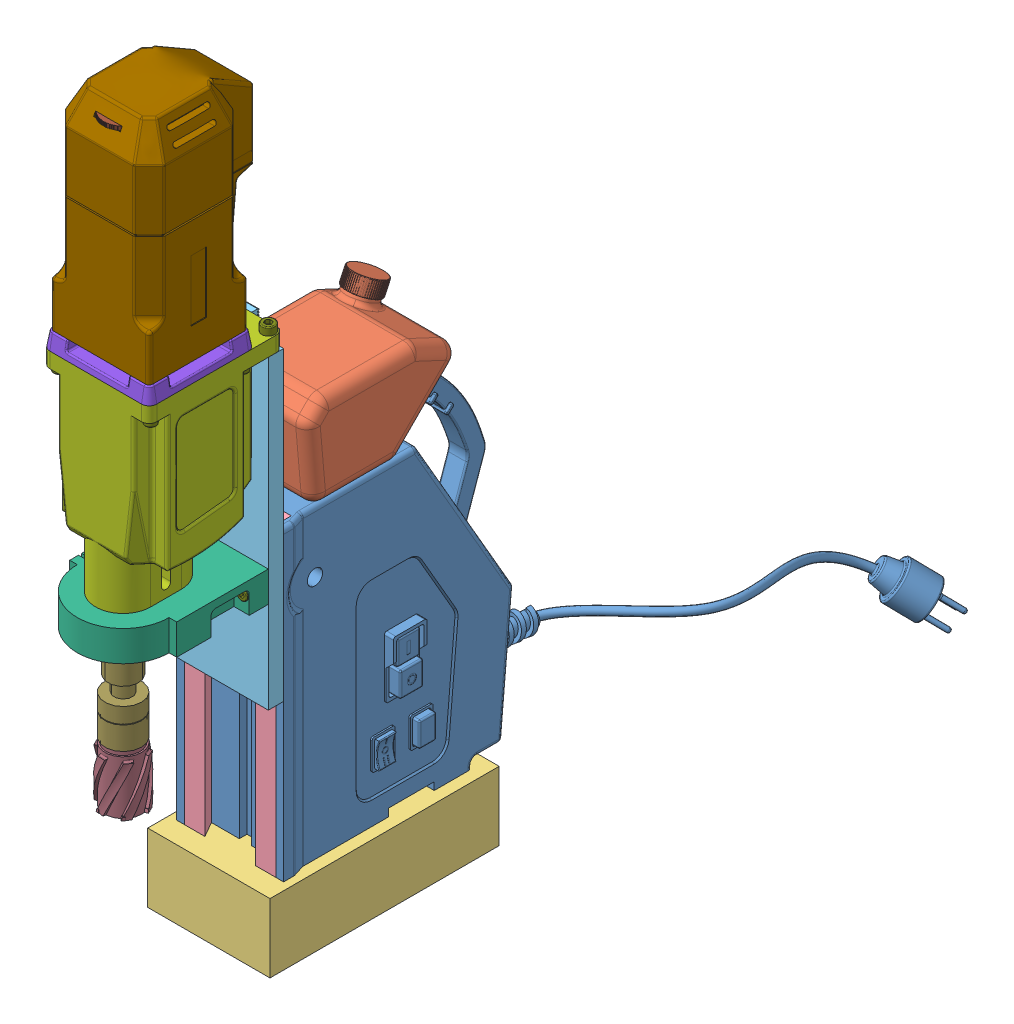
SolidWorks assembly Mag Drill, configuration Default. Lengths in mm.
Overall size (118.4 508.31 511.36).
24 component instances, 17 part files, 55 mates.
Components (placement in the parent):
- base-1: base [Default] at (-29.8336 -124.779 100.0225) size (112.65 272.37 411.36)
- water tank-1: water tank [Default] at (-29.8336 75.221 80.0225) size (75 87.59 99.86)
- Bottom electomagnit-1: Bottom electomagnit [Default] at (-29.8336 -169.779 38.9505) x (0 0 1) z (-1 0 0) size (150 45 80)
- fixed plate-1: fixed plate [Default] at (-29.8336 -124.779 95.0225) x (-1 0 0) z (0 0 -1) size (60 200 10)
- sliding plate-1: sliding plate [Default] at (-29.8336 177.5573 90.0225) x (1 0 0) z (0 0 -1) size (70 200 25)
- drill fixed plate-1: drill fixed plate [Default] at (-29.8336 37.5573 140.0225) x (-1 0 0) z (0 0 -1) size (70 20 90)
- drill floor fixed platform-1: drill floor fixed platform [Default] at (-29.8336 57.5573 160.0225) size (70.5 130 88)
- motor fixing plate-1: motor fixing plate [Default] at (-29.8336 187.5573 153.0225) size (70 10 70)
- motor-1: motor [默认] at (-29.8336 227.5573 153.0225) x (0 0 -1) z (0 -1 0) size (81.35 64.8 162.97)
- knob-1: knob [Default] at (-60.8336 142.5573 150.0225) x (-1 0 0) z (0 -0.897784 -0.440436) size (10 29 29)
- knob2-2: knob2 [Default] at (-29.8336 327.5573 170.4201) x (0.971097 0 0.238684) z (-0.238684 0 0.971097) size (24.99 2.5 24.99)
- drill fixture-1: drill fixture [Default] at (-29.8336 35.5573 170.0225) x (-0.675418 0 -0.737435) z (-0.737435 0 0.675418) size (24 110.5 24)
- drill-1: drill [Default] at (-29.8336 -62.9427 170.0225) x (0.989156 0 0.146869) z (-0.146869 0 0.989156) size (27.89 50.01 31.09)
- angular contact ball bearings gb-1: angular contact ball bearings gb [Rolling bearings S7200 GB 292-94] at (-29.8336 42.0573 170.0225) x (0 -1 0) z (0 0 1) size (9 30 30)
- cross recessed pan head screws gb-1: cross recessed pan head screws gb [GB_CROSS_SCREWS_TYPE1 M6X14-14  H type-S] at (-66.9336 35.221 77.0225) x (1 0 0) z (0 0.76934 0.638839) size (18.56 12 12)
- hexagon socket head cap screws gb-1: hexagon socket head cap screws gb [GB_FASTENER_SCREWS_HSHCS M4X10-S] at (0.1664 173.5573 182.0225) x (0 1 0) z (0 0 1) size (14 7 7)
- hexagon socket head cap screws gb-2: hexagon socket head cap screws gb [GB_FASTENER_SCREWS_HSHCS M4X10-S] at (-59.8336 173.5573 182.0225) x (0 1 0) z (0 0 1) size (14 7 7)
- hexagon socket head cap screws gb-3: hexagon socket head cap screws gb [GB_FASTENER_SCREWS_HSHCS M4X10-S] at (0.1664 173.5573 122.0225) x (0 1 0) z (0 0 1) size (14 7 7)
- hexagon socket head cap screws gb-4: hexagon socket head cap screws gb [GB_FASTENER_SCREWS_HSHCS M4X10-S] at (-59.8336 173.5573 122.0225) x (0 1 0) z (0 0 1) size (14 7 7)
- hexagon socket head cap screws gb-6: hexagon socket head cap screws gb [GB_FASTENER_SCREWS_HSHCS M5X12-S] at (0.1664 192.5573 105.0225) x (0 -1 0) z (-0.996731 0 -0.080796) size (17 8.5 8.5)
- hexagon socket head cap screws gb-7: hexagon socket head cap screws gb [GB_FASTENER_SCREWS_HSHCS M5X12-S] at (-59.8336 192.5573 105.0225) x (0 -1 0) z (-0.996731 0 -0.080796) size (17 8.5 8.5)
- hexagon socket head cap screws gb-8: hexagon socket head cap screws gb [GB_FASTENER_SCREWS_HSHCS M4X6-S] at (-60.8336 47.5573 123.5225) x (0 0 -1) z (1 0 0) size (10 7 7)
- hexagon socket head cap screws gb-11: hexagon socket head cap screws gb [GB_FASTENER_SCREWS_HSHCS M4X6-S] at (1.1664 47.5573 123.5225) x (0 0 -1) z (1 0 0) size (10 7 7)
- hexagon socket button head screws gb-1: hexagon socket button head screws gb [GB_SOCKET_TYPE7 M3X12-S] at (-60.8336 47.5573 166.6725) x (0 0 -1) z (0.073283 0.997311 0) size (13.65 5.7 5.7)
Mates (geometry in assembly coordinates):
- 重合1: coincident aligned: plane of base-1 through (-29.8336 -124.779 100.0225) normal (1 0 0); plane of water tank-1 through (-29.8336 75.221 80.0225) normal (1 0 0)
- 重合2: coincident aligned: plane of base-1 through (2.6664 75.221 100.0225) normal (0 1 0); plane of water tank-1 through (-29.8336 75.221 80.0225) normal (0 1 0)
- 距离1: distance = 10 mm: plane of assembly; plane of base-1 through (0.1664 -124.78 90.0225) normal (0 0 1); plane of water tank-1 through (-29.8336 75.221 80.0225) normal (0 0 1)
- 重合3: coincident anti-aligned: plane of base-1 through (2.6664 -124.779 -26.0495) normal (0 -1 0); plane of Bottom electomagnit-1 through (-29.8336 -124.779 38.9505) normal (0 1 0)
- 重合6: coincident anti-aligned: plane of base-1 through (-29.8336 -124.779 100.0225) normal (1 0 0); plane of Bottom electomagnit-1 through (-29.8336 -169.779 38.9505) normal (-1 0 0)
- 距离4: distance = 10 mm aligned: plane of base-1 through (2.6664 -119.779 -26.0495) normal (0 0 -1); plane of Bottom electomagnit-1 through (10.1664 -124.779 -36.0495) normal (0 0 -1)
- 重合10: coincident: plane of assembly; plane of base-1 through (0.1664 -124.78 90.0225) normal (0 0 1); plane of fixed plate-1 through (0.1664 75.221 90.0225) normal (0 0 -1)
- 重合11: coincident anti-aligned: plane of base-1 through (0.1664 -124.78 100.0225) normal (-1 0 0); plane of fixed plate-1 through (0.1664 75.221 100.0225) normal (1 0 0)
- 重合12: coincident: line of base-1 through (0.1664 75.221 90.0225) axis (-1 0 0); plane of fixed plate-1 through (-29.8336 75.221 95.0225) normal (0 1 0)
- 重合13: coincident anti-aligned: plane of sliding plate-1 through (-7.5601 -22.4427 90.0225) normal (0.866025 0 0.5); plane of fixed plate-1 through (-7.5601 -124.78 90.0225) normal (-0.866025 0 -0.5)
- 平行1: parallel anti-aligned: plane of fixed plate-1 through (-29.8336 75.221 95.0225) normal (0 1 0); plane of sliding plate-1 through (-29.8336 -22.4427 90.0225) normal (0 -1 0)
- 重合16: coincident anti-aligned: plane of base-1 through (0.1664 -124.78 90.0225) normal (0 0 1); plane of sliding plate-1 through (-52.1071 -22.4427 90.0225) normal (0 0 -1)
- 重合17: coincident anti-aligned: plane of sliding plate-1 through (-64.8336 248.268 110.0225) normal (0 0 1); plane of drill fixed plate-1 through (-29.8336 57.5573 110.0225) normal (0 0 -1)
- 平行2: parallel anti-aligned: plane of sliding plate-1 through (-29.8336 -22.4427 90.0225) normal (0 -1 0); plane of drill fixed plate-1 through (-29.8336 57.5573 140.0225) normal (0 1 0)
- 重合19: coincident aligned: plane of sliding plate-1 through (5.1664 248.268 110.0225) normal (1 0 0); plane of drill fixed plate-1 through (5.1664 57.5573 140.0225) normal (1 0 0)
- 同心1: concentric aligned: cylinder of sliding plate-1; cylinder of drill fixed plate-1 through (1.1664 47.5573 77.5225) axis (0 0 1) radius 2
- 重合20: coincident anti-aligned: plane of drill fixed plate-1 through (-29.8336 57.5573 140.0225) normal (0 1 0); plane of drill floor fixed platform-1 through (-29.8336 57.5573 150.0225) normal (0 -1 0)
- 同心2: concentric aligned: cylinder of drill fixed plate-1 through (-29.8336 57.5573 170.0225) axis (0 -1 0) radius 15; cylinder of drill floor fixed platform-1 through (-29.8336 87.5573 170.0225) axis (0 -1 0) radius 18
- 平行4: parallel aligned: plane of drill fixed plate-1 through (5.1664 57.5573 140.0225) normal (1 0 0); plane of drill floor fixed platform-1 through (-11.8336 87.5573 150.0225) normal (1 0 0)
- 重合24: coincident anti-aligned: plane of drill floor fixed platform-1 through (-29.8336 187.5573 160.0225) normal (0 1 0); plane of motor fixing plate-1 through (-59.8336 187.5573 183.0225) normal (0 -1 0)
- 重合25: coincident: plane of drill floor fixed platform-1 through (-64.8336 177.5573 188.0225) normal (0 0 1); line of motor fixing plate-1 through (-59.8336 187.5573 188.0225) axis (1 0 0)
- 重合26: coincident: plane of drill floor fixed platform-1 through (5.1664 177.5573 110.0225) normal (1 0 0); line of motor fixing plate-1 through (5.1664 187.5573 183.0225) axis (0 0 -1)
- 重合27: coincident anti-aligned: plane of motor fixing plate-1 through (-59.8336 197.5573 183.0225) normal (0 1 0); plane of motor-1 through (-29.8336 197.5573 153.0225) normal (0 -1 0)
- 同心3: concentric aligned: cone of motor fixing plate-1 through (0.1664 187.5573 123.0225) axis (0 1 0); cylinder of motor-1 through (0.1664 197.5573 123.0225) axis (0 1 0) radius 2.3976
- 同心4: concentric aligned: cone of motor fixing plate-1 through (-59.8336 187.5573 123.0225) axis (0 1 0); cylinder of motor-1 through (-59.8336 197.5573 123.0225) axis (0 1 0) radius 2.3976
- 重合28: coincident anti-aligned: plane of drill floor fixed platform-1 through (-60.8336 142.5573 150.0225) normal (-1 0 0); plane of knob-1 through (-60.8336 142.5573 150.0225) normal (1 0 0)
- 同心5: concentric anti-aligned: circle of drill floor fixed platform-1; cylinder of knob-1 through (-65.8336 142.5573 150.0225) axis (1 0 0) radius 14.5
- 重合32: coincident anti-aligned: plane of motor-1 through (-29.8336 330.0573 170.4201) normal (0 -1 0); plane of knob2-2 through (-29.8336 330.0573 170.4201) normal (0 1 0)
- 同心9: concentric anti-aligned: circle of motor-1; circle of knob2-2
- 同心10: concentric anti-aligned: cylinder of drill fixed plate-1 through (-29.8336 57.5573 170.0225) axis (0 -1 0) radius 15; cylinder of drill fixture-1 through (-29.8336 10.5573 170.0225) axis (0 1 0) radius 10
- 同心11: concentric anti-aligned: cylinder of drill fixed plate-1 through (-29.8336 57.5573 170.0225) axis (0 -1 0) radius 15; cylinder of angular contact ball bearings gb-1 through (-29.8336 45.0497 170.0225) axis (0 1 0) radius 5
- 重合34: coincident aligned: plane of drill fixed plate-1 through (-29.8336 37.5573 140.0225) normal (0 -1 0); plane of angular contact ball bearings gb-1 through (-21.5003 37.5573 170.0225) normal (0 -1 0)
- 距离5: distance = 2 mm anti-aligned: plane of drill fixture-1 through (-29.8336 35.5573 170.0225) normal (0 1 0); plane of drill fixed plate-1 through (-29.8336 37.5573 140.0225) normal (0 -1 0)
- 同心12: concentric aligned: cylinder of drill fixture-1 through (-29.8336 -12.9427 170.0225) axis (0 -1 0) radius 11; cylinder of drill-1 through (-29.8336 -12.9427 170.0225) axis (0 -1 0) radius 11
- 重合39: coincident anti-aligned: plane of drill fixture-1 through (-29.8336 -12.9427 170.0225) normal (0 -1 0); plane of drill-1 through (-29.8336 -12.9427 170.0225) normal (0 1 0)
- 同心14: concentric anti-aligned: cylinder of base-1 through (-52.3336 35.221 77.0225) axis (-1 0 0) radius 5; circle of cross recessed pan head screws gb-1
- 重合41: coincident anti-aligned: plane of base-1 through (-62.3336 -124.779 100.0225) normal (-1 0 0); plane of cross recessed pan head screws gb-1 through (-62.3336 37.3931 74.4067) normal (1 0 0)
- 同心15: concentric aligned: cylinder of drill floor fixed platform-1 through (0.1664 187.5573 182.0225) axis (0 -1 0) radius 2; cylinder of hexagon socket head cap screws gb-1 through (0.1664 177.5573 182.0225) axis (0 -1 0) radius 3.5
- 重合42: coincident anti-aligned: plane of drill floor fixed platform-1 through (-29.8336 177.5573 160.0225) normal (0 -1 0); plane of hexagon socket head cap screws gb-1 through (0.1664 177.5573 182.0225) normal (0 1 0)
- 重合43: coincident anti-aligned: plane of drill floor fixed platform-1 through (-29.8336 177.5573 160.0225) normal (0 -1 0); plane of hexagon socket head cap screws gb-2 through (-59.8336 177.5573 182.0225) normal (0 1 0)
- 同心16: concentric aligned: cylinder of drill floor fixed platform-1 through (-59.8336 187.5573 182.0225) axis (0 -1 0) radius 2; cylinder of hexagon socket head cap screws gb-2 through (-59.8336 177.5573 182.0225) axis (0 -1 0) radius 3.5
- 同心17: concentric aligned: cylinder of drill floor fixed platform-1 through (0.1664 187.5573 122.0225) axis (0 -1 0) radius 2; cylinder of hexagon socket head cap screws gb-3 through (0.1664 177.5573 122.0225) axis (0 -1 0) radius 3.5
- 重合44: coincident anti-aligned: plane of drill floor fixed platform-1 through (-29.8336 177.5573 160.0225) normal (0 -1 0); plane of hexagon socket head cap screws gb-3 through (0.1664 177.5573 122.0225) normal (0 1 0)
- 同心18: concentric aligned: cylinder of drill floor fixed platform-1 through (-59.8336 187.5573 122.0225) axis (0 -1 0) radius 2; cylinder of hexagon socket head cap screws gb-4 through (-59.8336 177.5573 122.0225) axis (0 -1 0) radius 3.5
- 重合45: coincident anti-aligned: plane of drill floor fixed platform-1 through (-29.8336 177.5573 160.0225) normal (0 -1 0); plane of hexagon socket head cap screws gb-4 through (-59.8336 177.5573 122.0225) normal (0 1 0)
- 同心20: concentric anti-aligned: cylinder of drill floor fixed platform-1 through (0.1664 337.5573 105.0225) axis (0 -1 0) radius 2.5; cylinder of hexagon socket head cap screws gb-6 through (0.1664 187.5573 105.0225) axis (0 1 0) radius 4.25
- 重合46: coincident anti-aligned: plane of drill floor fixed platform-1 through (-29.8336 187.5573 160.0225) normal (0 1 0); plane of hexagon socket head cap screws gb-6 through (0.1664 187.5573 105.0225) normal (0 -1 0)
- 重合47: coincident anti-aligned: plane of drill floor fixed platform-1 through (-29.8336 187.5573 160.0225) normal (0 1 0); plane of hexagon socket head cap screws gb-7 through (-59.8336 187.5573 105.0225) normal (0 -1 0)
- 同心21: concentric anti-aligned: cylinder of drill floor fixed platform-1 through (-59.8336 337.5573 105.0225) axis (0 -1 0) radius 2.5; cylinder of hexagon socket head cap screws gb-7 through (-59.8336 187.5573 105.0225) axis (0 1 0) radius 4.25
- 重合48: coincident anti-aligned: plane of drill fixed plate-1 through (-60.8336 47.5573 119.5225) normal (0 0 1); plane of hexagon socket head cap screws gb-8 through (-60.8336 47.5573 119.5225) normal (0 0 -1)
- 同心22: concentric anti-aligned: cylinder of drill fixed plate-1 through (-60.8336 47.5573 125.5225) axis (0 0 -1) radius 3; cylinder of hexagon socket head cap screws gb-8 through (-60.8336 47.5573 119.5225) axis (0 0 1) radius 3.5
- 重合51: coincident anti-aligned: plane of drill fixed plate-1 through (1.1664 47.5573 119.5225) normal (0 0 1); plane of hexagon socket head cap screws gb-11 through (1.1664 47.5573 119.5225) normal (0 0 -1)
- 同心26: concentric aligned: cylinder of drill fixed plate-1 through (1.1664 47.5573 77.5225) axis (0 0 1) radius 2; cylinder of hexagon socket head cap screws gb-11 through (1.1664 47.5573 119.5225) axis (0 0 1) radius 3.5
- 同心28: concentric anti-aligned: cylinder of drill fixed plate-1 through (-60.8336 47.5573 223.0225) axis (0 0 -1) radius 3; circle of hexagon socket button head screws gb-1
- 重合52: coincident anti-aligned: plane of drill fixed plate-1 through (-60.8336 47.5573 165.0225) normal (0 0 1); plane of hexagon socket button head screws gb-1 through (-60.8336 47.5573 165.0225) normal (0 0 -1)
